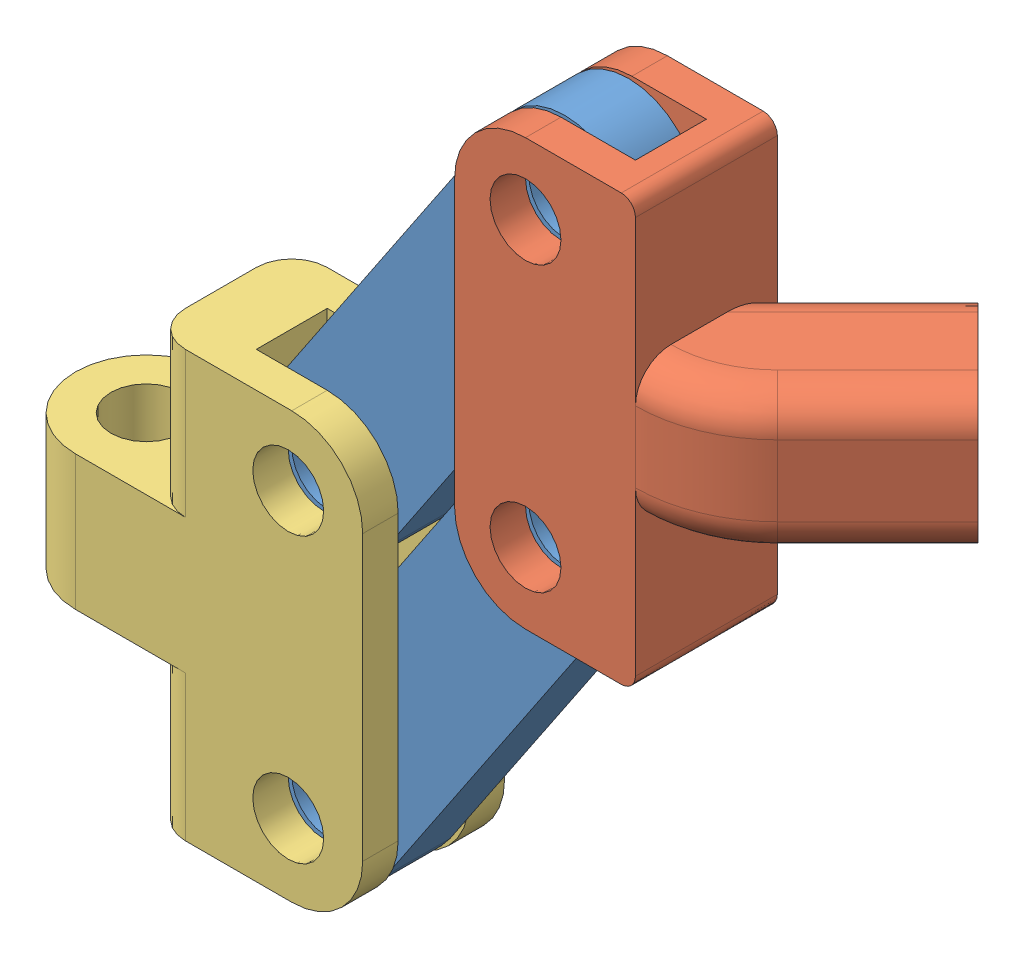
SolidWorks assembly Leg Assembly, configuration S1. Lengths in mm.
Overall size (117.23 117.57 34.14).
4 component instances, 3 part files, 11 mates.
Components (placement in the parent):
- Arm-1: Arm [Default] at (46.7229 4.9068 0) x (0.557428 0.830225 0) z (0 0 1) size (80 20 9)
- LowerJoint-1: LowerJoint [S1] at (63.4457 49.8135 0) x (-1 0 0) z (0 0 -1) size (53.78 60 34.14)
- UpperJoint-1: UpperJoint [Default] at origin size (50.5 60 20)
- Arm-2: Arm [Default] at (46.7229 44.9068 0) x (0.557428 0.830225 0) z (0 0 1) size (80 20 9)
Mates (geometry in assembly coordinates):
- Coincident1: coordinate: point of UpperJoint-1
- Concentric1: concentric anti-aligned: cylinder of UpperJoint-1 through (30 20 -10) axis (0 0 1) radius 5; cylinder of Arm-2 through (30 20 4.5) axis (0 0 -1) radius 5
- Concentric2: concentric anti-aligned: cylinder of Arm-1 through (30 -20 4.5) axis (0 0 -1) radius 5; cylinder of UpperJoint-1 through (30 -20 -10) axis (0 0 1) radius 5
- Width1: width anti-aligned: plane of UpperJoint-1 through (0 30 5) normal (0 0 -1); plane of UpperJoint-1 through (0 30 -5) normal (0 0 1); plane of Arm-2 through (30 20 4.5) normal (0 0 1); plane of Arm-2 through (30 20 -4.5) normal (0 0 -1)
- Coincident2: coincident aligned: plane of Arm-1 through (30 -20 -4.5) normal (0 0 -1); plane of Arm-2 through (30 20 -4.5) normal (0 0 -1)
- Concentric3: concentric anti-aligned: cylinder of LowerJoint-1 through (63.4457 69.8135 -10) axis (0 0 1) radius 5; cylinder of Arm-2 through (63.4457 69.8135 4.5) axis (0 0 -1) radius 5
- Concentric4: concentric anti-aligned: cylinder of Arm-1 through (63.4457 29.8135 4.5) axis (0 0 -1) radius 5; cylinder of LowerJoint-1 through (63.4457 29.8135 -10) axis (0 0 1) radius 5
- Width2: width aligned: plane of Arm-2 through (30 20 4.5) normal (0 0 1); plane of LowerJoint-1 through (30 20 -4.5) normal (0 0 -1); plane of Arm-2 through (63.4457 69.8135 -5) normal (0 0 1); plane of LowerJoint-1 through (63.4457 69.8135 5) normal (0 0 -1)
- Concentric5: concentric aligned: cylinder of LowerJoint-1 through (148.7862 37.0247 10) axis (0 0 -1) radius 5; cylinder of Arm-2 through (148.7862 37.0247 4.5) axis (0 0 -1) radius 5
- Concentric6: concentric aligned: cylinder of Arm-1 through (148.7862 -2.9753 4.5) axis (0 0 -1) radius 5; cylinder of LowerJoint-1 through (148.7862 -2.9753 10) axis (0 0 -1) radius 5
- Width3: width anti-aligned: plane of LowerJoint-1 through (148.7862 37.0247 5) normal (0 0 -1); plane of LowerJoint-1 through (148.7862 37.0247 -5) normal (0 0 1); plane of Arm-2 through (30 20 4.5) normal (0 0 1); plane of Arm-2 through (30 20 -4.5) normal (0 0 -1)
